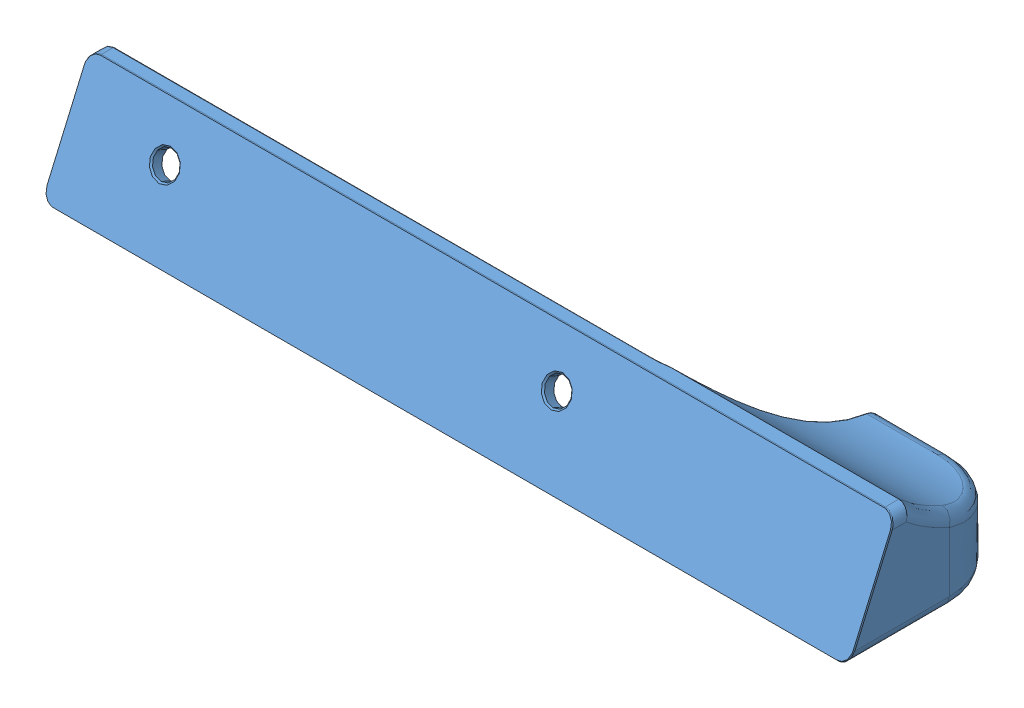
SolidWorks assembly 040M01C04P001 HES Trigger, configuration Default. Lengths in mm.
Overall size (103 14.75 21.67).
2 component instances, 2 part files, 4 mates.
Components (placement in the parent):
- 040M01C04P003E Magnet Holder-1: 040M01C04P003E Magnet Holder [Predeterminado] at (0 -3.15 0) size (103 14.75 21.67)
- Magnet (Supermagnete = R-15-06-06-N)-1: Magnet (Supermagnete = R-15-06-06-N) [Predeterminado] at origin size (15 6 15)
Mates (geometry in assembly coordinates):
- Concentric1: concentric: cylinder of Magnet (Supermagnete = R-15-06-06-N)-1 through (0 3 0) axis (0 -1 0) radius 7.5; line of 040M01C04P003E Magnet Holder-1 through (13.5397 0 -8.0741) axis (0 0 1)
- Symmetric1: symmetric: plane of 040M01C04P003E Magnet Holder-1 through (-28.35 3.15 -7.65) normal (0 -1 0); plane of 040M01C04P003E Magnet Holder-1 through (-28.35 -3.15 -7.65) normal (0 1 0); plane of Magnet (Supermagnete = R-15-06-06-N)-1 through (0 0 0) normal (0 1 0)
- Coincident1: coordinate: point of Magnet (Supermagnete = R-15-06-06-N)-1; point of assembly
- Coincident2: coincident: plane of 040M01C04P003E Magnet Holder-1 through (0 -3.15 0) normal (0 0 1); plane of assembly through (0 0 0) normal (0 0 1)
